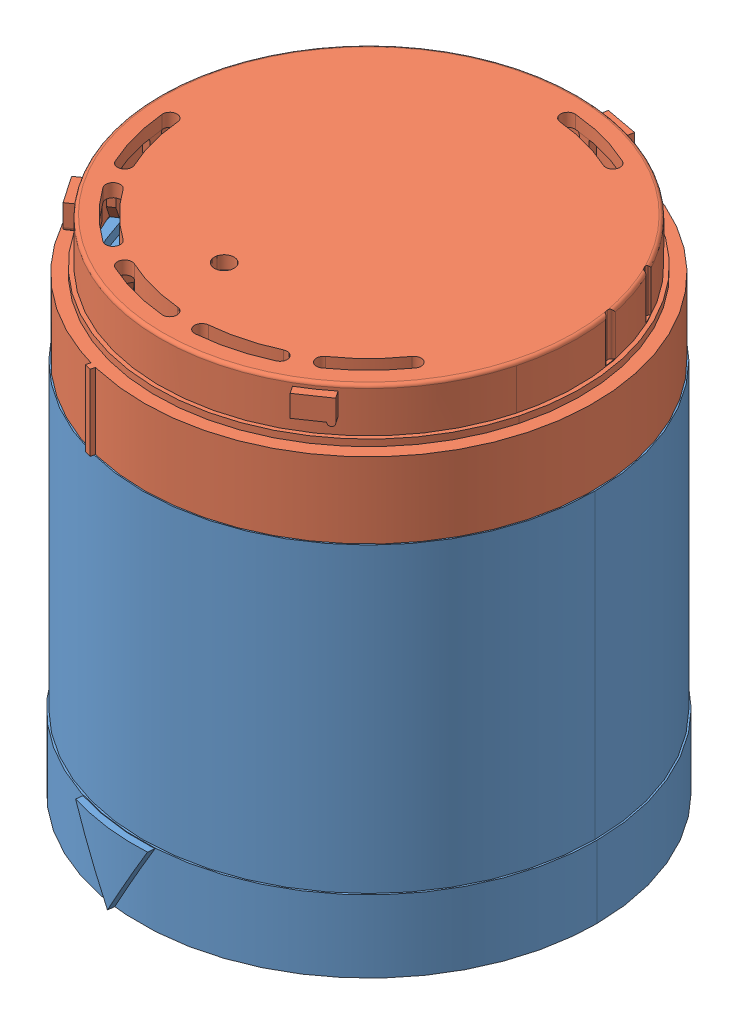
SolidWorks assembly 855t_module, configuration Default. Lengths in mm.
Overall size (84.2 76.26 84.69).
3 component instances, 2 part files, 0 mates.
Components (placement in the parent):
- 855t_module(2)^855t_module-1: 855t_module(2)^855t_module [Default] at origin size (84.2 76.26 84.69) (virtual)
  - 40378-011^855t_module(2)_855t_module-1: 40378-011^855t_module(2)_855t_module [Default] at origin size (69.5 65.01 72.38) (virtual)
  - 40378-007^855t_module(2)_855t_module-1: 40378-007^855t_module(2)_855t_module [Default] at (0 57 0) x (0.965926 0 0.258819) z (-0.258819 0 0.965926) size (68.6 19.75 69.3) (virtual)
